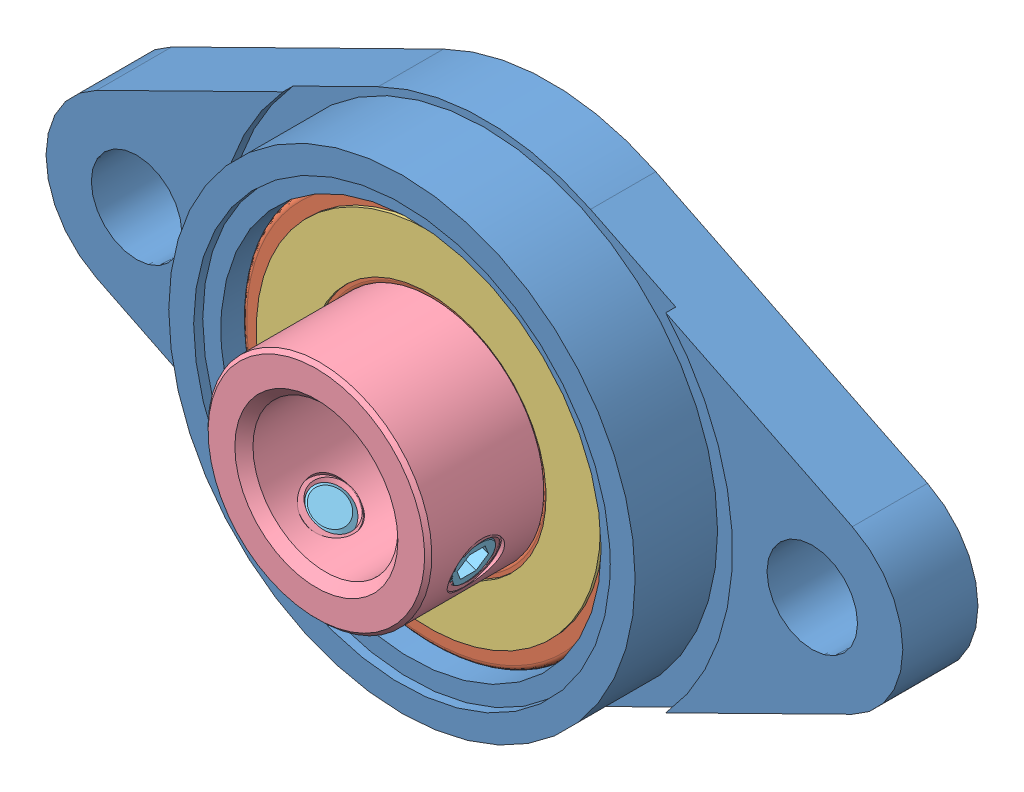
SolidWorks assembly Zinc Alloy Pillow Block Flange Bearing KFL08 ID-8mm, configuration Default. Lengths in mm.
Overall size (47.3 26.5 12.88).
9 component instances, 5 part files, 0 mates.
Components (placement in the parent):
- Zinc Alloy Pillow Block Flange Bearing KFL08 ID-8mm.stp-1: Zinc Alloy Pillow Block Flange Bearing KFL08 ID-8mm.stp [Default] at origin size (47.3 26.5 12.88)
  - Flange.stp-1: Flange.stp [Default] x (-1 0 0) z (0 0 1) size (47.3 26.5 8.16)
  - Bearing 61801-2Z GB_T 276-94.stp-1: Bearing 61801-2Z GB_T 276-94.stp [Default] at (0 0 1.525) x (0 0 1) z (-0.985741 0.16827 0) size (5 21 21)
  - DIN 988 - 13 x 19 x 1.stp-1: DIN 988 - 13 x 19 x 1.stp [Default] at (0 0 5.6917) x (-0.369618 -0.929184 0) z (0 0 1) size (19 19 1)
  - DIN 988 - 13 x 19 x 1.stp-2: DIN 988 - 13 x 19 x 1.stp [Default] at (0 0 1.3583) x (0.999993 0.003767 0) z (0 0 1) size (19 19 1)
  - Collar 8x12.35x11.35.stp-1: Collar 8x12.35x11.35.stp [Default] at (0 0 1.525) x (0.825043 -0.56507 0) z (-0.56507 -0.825043 0) size (12.36 11.35 12.36)
  - IS_ 6094 - M3 x 2(1).stp-1: IS_ 6094 - M3 x 2(1).stp [Default] at (3.7491 -1.3208 9.875) x (0.943181 -0.332278 0) z (0 0 1) size (2 3 3)
  - IS_ 6094 - M3 x 2(1).stp-2: IS_ 6094 - M3 x 2(1).stp [Default] at (-2.2462 -3.2795 9.875) x (-0.56507 -0.825043 0) z (0 0 1) size (2 3 3)
  - IS_ 6094 - M3 x 2(1).stp-3: IS_ 6094 - M3 x 2(1).stp [Default] at (3.7491 -1.3208 9.875) x (0.943181 -0.332278 0) z (0 0 1) size (2 3 3)
